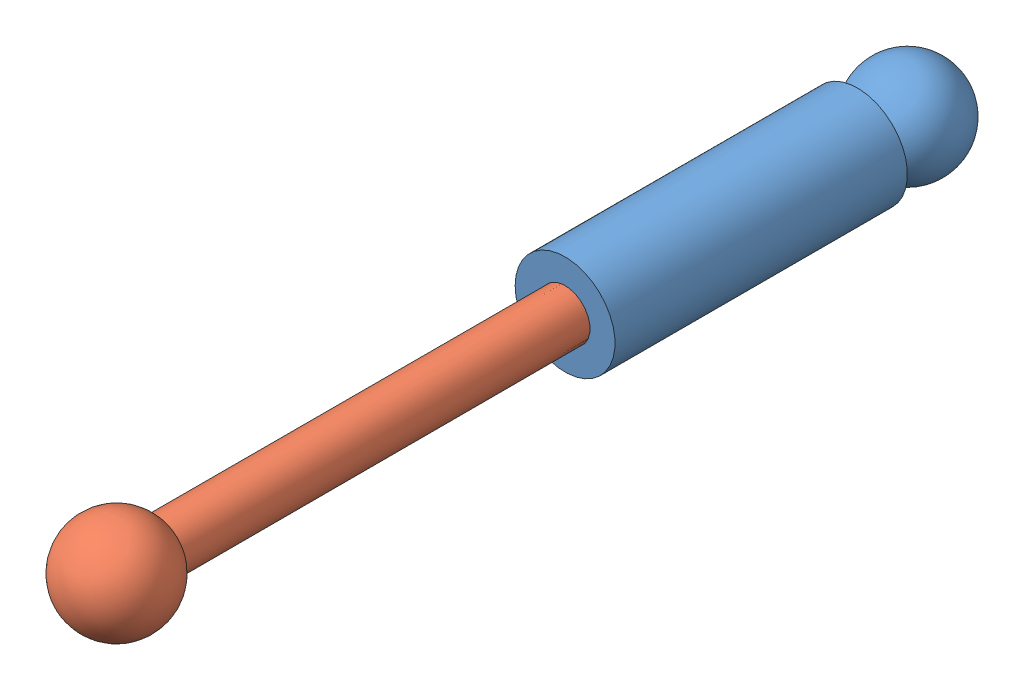
SolidWorks assembly PairedStrut, configuration Default. Lengths in mm.
Overall size (8.3 8.3 56.64).
2 component instances, 2 part files, 2 mates.
Components (placement in the parent):
- StrutExternal2-1: StrutExternal2 [Default] at (17.8005 21.4275 8.953) size (6.35 6.35 24.94)
- StrutInternal2-1: StrutInternal2 [Default] at (17.8005 21.4275 59.245) x (-0.923728 -0.383049 0) z (0 0 -1) size (6.35 6.35 31.75)
Mates (geometry in assembly coordinates):
- Distance1: distance = 18.542 mm: plane of StrutExternal2-1 through (17.8005 21.4275 12.128) normal (0 0 1); plane of StrutInternal2-1 through (17.8005 21.4275 30.67) normal (0 0 -1)
- Concentric1: concentric: cylinder of StrutExternal2-1 through (17.8005 21.4275 8.953) axis (0 0 -1) radius 3.175; cylinder of StrutInternal2-1 through (17.8005 21.4275 59.245) axis (0 0 1) radius 1.5875
